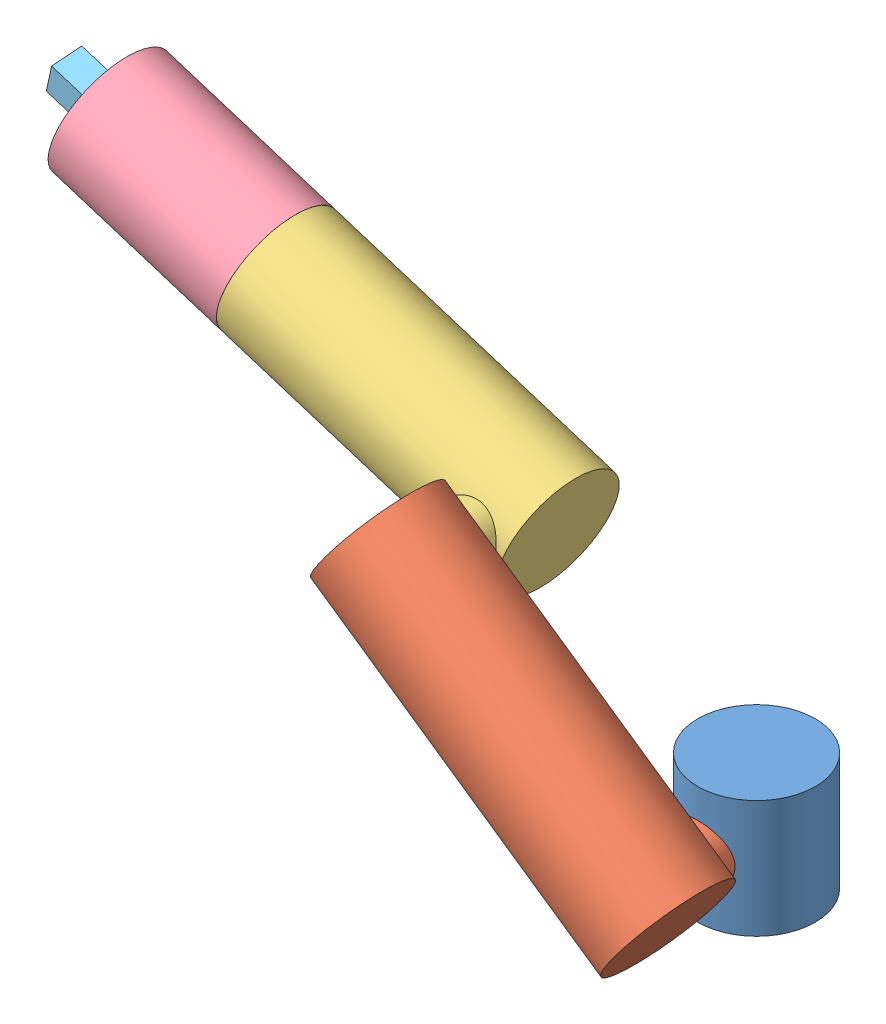
SolidWorks assembly skribbleai, configuration Default. Lengths in mm.
Overall size (64.63 35.84 20.55).
5 component instances, 5 part files, 9 mates.
Components (placement in the parent):
- ur5base-001-1: ur5base-001 [Default] at origin size (10 10 10)
- urf5link2-001-1: urf5link2-001 [Default] at (2.4684 3.2951 10) x (-0.568316 -0.82281 0) z (0 0 -1) size (10 30 15)
- urf5link3-001-1: urf5link3-001 [Default] at (-16.8853 17.7406 0) x (0.299651 0.954049 0) z (0 0 1) size (10 30 15)
- ur5link4-001-1: ur5link4-001 [Default] at (-40.7365 25.2319 0) x (-0.297596 -0.947506 -0.116913) z (0.035033 0.11154 -0.993142) size (10 15 10)
- endeff-001-1: endeff-001 [Default] at (-49.363 27.9414 0) x (-0.297596 -0.947506 -0.116913) z (0.035033 0.11154 -0.993142) size (2.5 10 2.5)
Mates (geometry in assembly coordinates):
- Concentric1: concentric anti-aligned: cylinder of ur5base-001-1 through (0 5 5) axis (0 0 -1) radius 2.5; cylinder of urf5link2-001-1 through (0 5 0) axis (0 0 1) radius 2.5
- Coincident1: coincident anti-aligned: plane of ur5base-001-1 through (0 5 0) normal (0 0 1); plane of urf5link2-001-1 through (0 5 0) normal (0 0 -1)
- Concentric2: concentric anti-aligned: cylinder of urf5link2-001-1 through (-19.7474 18.6396 0) axis (0 0 1) radius 2.5; cylinder of urf5link3-001-1 through (-19.7474 18.6396 10) axis (0 0 -1) radius 2.5
- Coincident2: coincident anti-aligned: plane of urf5link2-001-1 through (-19.7474 18.6396 10) normal (0 0 -1); plane of urf5link3-001-1 through (-19.7474 18.6396 10) normal (0 0 1)
- Concentric3: concentric aligned: cylinder of urf5link3-001-1 through (-45.5068 26.7302 0) axis (0.954049 -0.299651 0) radius 2.5; cylinder of ur5link4-001-1 through (-45.5068 26.7302 0) axis (0.954049 -0.299651 0) radius 2.5
- Coincident3: coincident anti-aligned: plane of urf5link3-001-1 through (-45.5068 26.7302 0) normal (-0.954049 0.299651 0); plane of ur5link4-001-1 through (-45.5068 26.7302 0) normal (0.954049 -0.299651 0)
- Parallel1: parallel anti-aligned: plane of ur5link4-001-1 through (-50.277 28.2284 0) normal (-0.954049 0.299651 0); plane of endeff-001-1 through (-49.363 27.9414 0) normal (0.954049 -0.299651 0)
- Coincident5: coincident anti-aligned: plane of ur5link4-001-1 through (-49.8612 29.5522 -1.0953) normal (-0.297596 -0.947506 -0.116913); plane of endeff-001-1 through (-58.4877 32.2617 -1.0953) normal (0.297596 0.947506 0.116913)
- Coincident7: coincident anti-aligned: plane of ur5link4-001-1 through (-49.9488 29.2734 1.3876) normal (0.035033 0.11154 -0.993142); plane of endeff-001-1 through (-58.5753 31.9828 1.3876) normal (-0.035033 -0.11154 0.993142)
